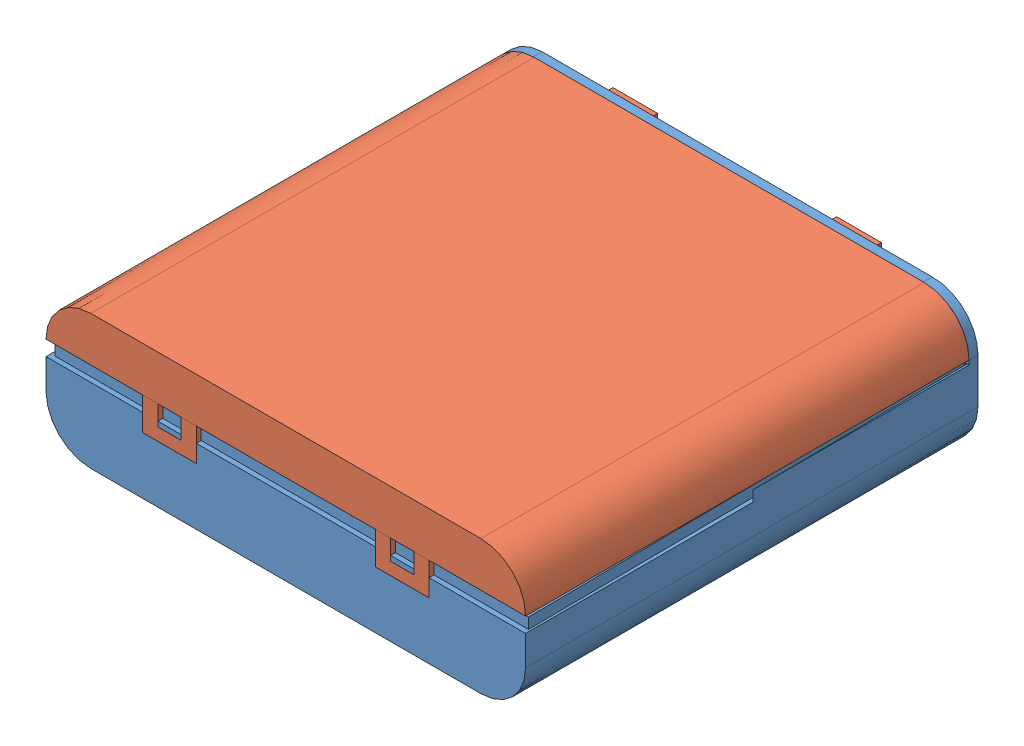
SolidWorks assembly Assem3, configuration Default. Lengths in mm.
Overall size (68.07 20.23 65.48).
2 component instances, 2 part files, 3 mates.
Components (placement in the parent):
- BATTERY PACK BASE-1: BATTERY PACK BASE [Default] at (30.4367 30.5702 52.9636) size (68.07 20.21 64.21)
- BATTERY PACK COVER-1: BATTERY PACK COVER [Default] at (30.4367 30.7272 53.5986) size (68.07 10.97 65.48)
Mates (geometry in assembly coordinates):
- Coincident12: coincident: point of BATTERY PACK BASE-1; point of BATTERY PACK COVER-1
- Coincident13: coincident: point of BATTERY PACK BASE-1; point of BATTERY PACK COVER-1
- Coincident14: coincident anti-aligned: plane of BATTERY PACK BASE-1 through (64.4727 49.4805 22.128) normal (0 0 1); plane of BATTERY PACK COVER-1 through (64.4727 49.6375 22.128) normal (0 0 -1)
